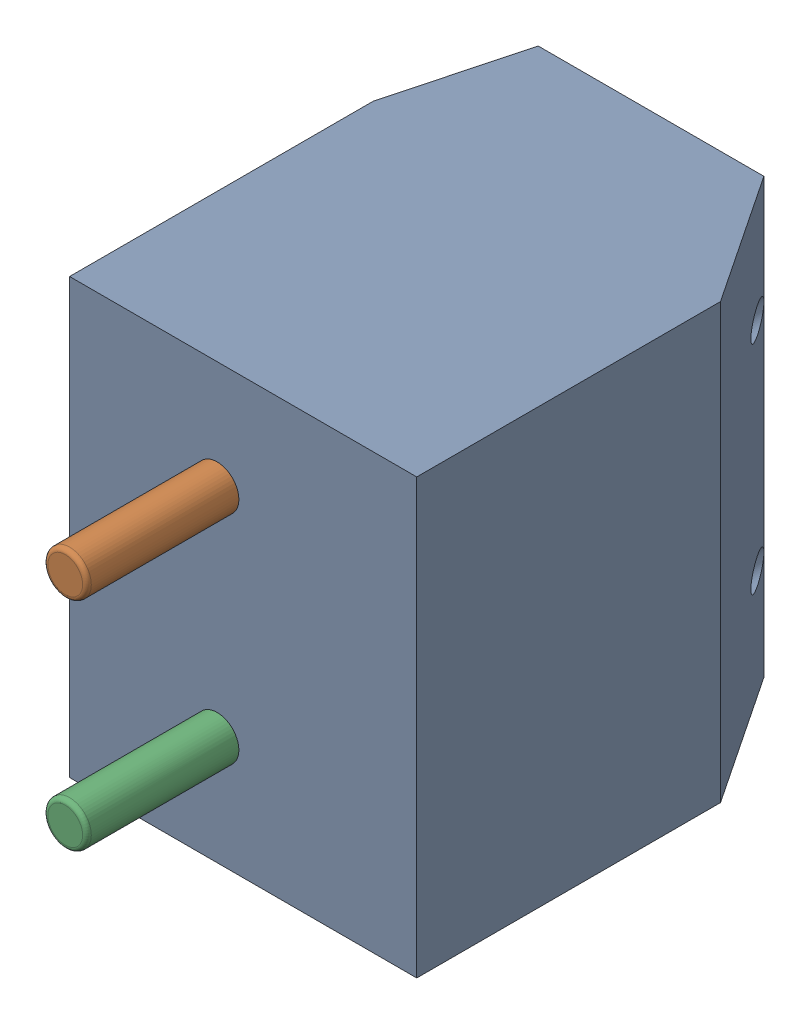
SolidWorks assembly J2, configuration Default. Lengths in mm.
Overall size (8 10 13.5).
4 component instances, 2 part files, 0 mates.
Components (placement in the parent):
- TB2-1: TB2 [Default] at (8.4073 42.6599 -11.7914) x (0 1 0) z (-1 0 0) size (10 13.5 8)
  - User_Library-TB2_TB_case_1-1: User_Library-TB2_TB_case_1 [Default] at (-10 0 0) x (0 0 1) z (0 1 0) size (8 10 10)
  - User_Library-TB2_TB_screw_1-1: User_Library-TB2_TB_screw_1 [Default] at (-2.5 -4.6 4.6) x (-1 0 0) z (0 0 -1) size (3.9 11.9 3.9)
  - User_Library-TB2_TB_screw_1-2: User_Library-TB2_TB_screw_1 [Default] at (-7.5 -4.6 4.6) size (3.9 11.9 3.9)
